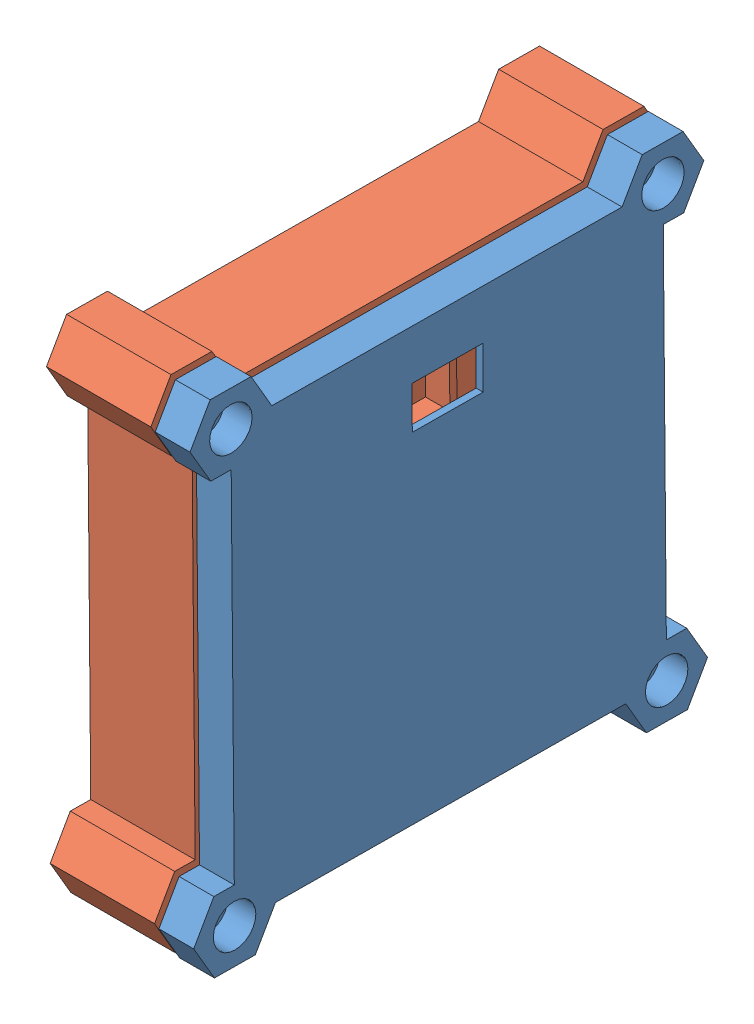
SolidWorks assembly assembly, configuration Default. Lengths in mm.
Overall size (22.25 71.23 73.1).
2 component instances, 2 part files, 2 mates.
Components (placement in the parent):
- back_vol_3-1: back_vol_3 [Default] at (-22.0973 -25.8221 50.9975) x (-0.008726 0.999962 -0.000076) z (0.008727 0 -0.999962) size (71 6 72.55)
- back_vol_3 - Copy-1: back_vol_3 - Copy [Default] at (-23.0935 -25.8809 50.6199) x (-0.008726 0.999962 -0.000076) z (-0.008727 0 0.999962) size (71 15 72.55)
Mates (geometry in assembly coordinates):
- Distance2: distance = 1 mm anti-aligned: plane of back_vol_3 - Copy-1 through (-23.0935 -25.8809 50.6199) normal (0.999924 0.008727 0.008726); plane of back_vol_3-1 through (-22.0973 -25.8221 50.9975) normal (-0.999924 -0.008727 -0.008726)
- Parallel6: parallel aligned: plane of back_vol_3-1 through (-17.0976 4.7204 20.5399) normal (-0.008726 0.999962 -0.000076); plane of back_vol_3 - Copy-1 through (-38.6247 4.487 80.9855) normal (-0.008726 0.999962 -0.000076)
